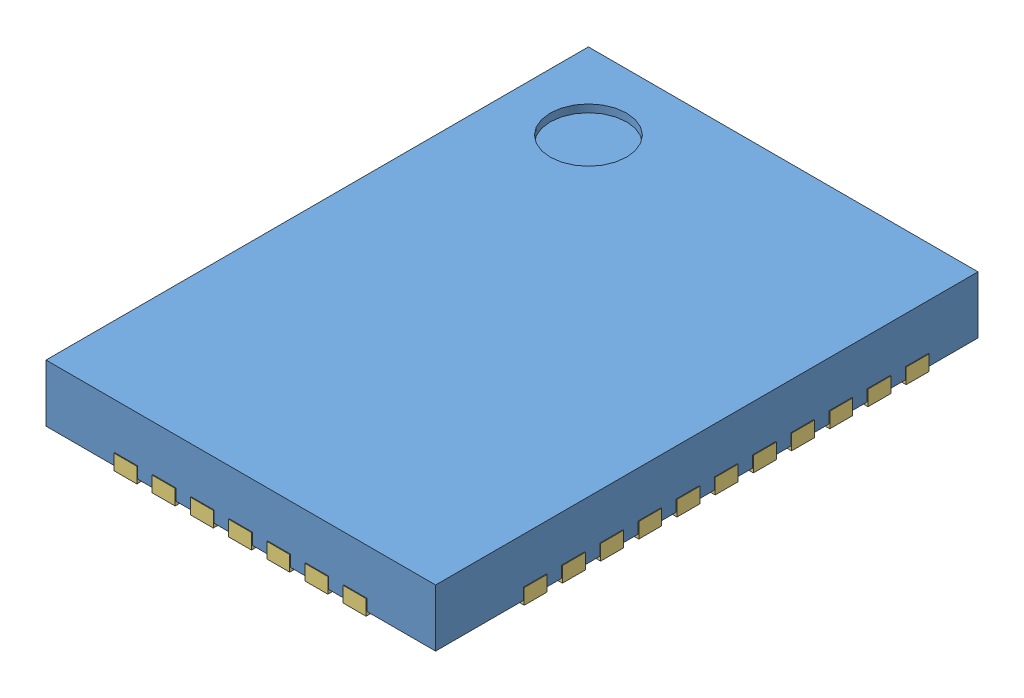
SolidWorks assembly LT-UHF38, configuration Default. Lengths in mm.
Overall size (5.12 0.8 7.12).
38 component instances, 3 part files, 12 mates.
Components (placement in the parent):
- Body-1: Body [Default] at (0 0.05 0) size (5.1 0.75 7.1)
- EP-1: EP [Default] at (0 0.2 0) x (-1 0 0) z (0 0 1) size (3.25 0.2 5.25)
- Pin-1: Pin [Default] at (-2.385 0 -2.75) size (0.5 0.2 0.3)
- Pin-2: Pin [Default] at (-2.385 0 -2.25) size (0.5 0.2 0.3)
- Pin-3: Pin [Default] at (-2.385 0 -1.75) size (0.5 0.2 0.3)
- Pin-4: Pin [Default] at (-2.385 0 -1.25) size (0.5 0.2 0.3)
- Pin-5: Pin [Default] at (-2.385 0 -0.75) size (0.5 0.2 0.3)
- Pin-6: Pin [Default] at (-2.385 0 -0.25) size (0.5 0.2 0.3)
- Pin-7: Pin [Default] at (-2.385 0 0.25) size (0.5 0.2 0.3)
- Pin-8: Pin [Default] at (-2.385 0 0.75) size (0.5 0.2 0.3)
- Pin-9: Pin [Default] at (-2.385 0 1.25) size (0.5 0.2 0.3)
- Pin-10: Pin [Default] at (-2.385 0 1.75) size (0.5 0.2 0.3)
- Pin-11: Pin [Default] at (-2.385 0 2.25) size (0.5 0.2 0.3)
- Pin-12: Pin [Default] at (2.385 0 -2.75) x (-1 0 0) z (0 0 -1) size (0.5 0.2 0.3)
- Pin-13: Pin [Default] at (2.385 0 -2.25) x (-1 0 0) z (0 0 -1) size (0.5 0.2 0.3)
- Pin-14: Pin [Default] at (2.385 0 -1.75) x (-1 0 0) z (0 0 -1) size (0.5 0.2 0.3)
- Pin-15: Pin [Default] at (2.385 0 -1.25) x (-1 0 0) z (0 0 -1) size (0.5 0.2 0.3)
- Pin-16: Pin [Default] at (2.385 0 -0.75) x (-1 0 0) z (0 0 -1) size (0.5 0.2 0.3)
- Pin-17: Pin [Default] at (2.385 0 -0.25) x (-1 0 0) z (0 0 -1) size (0.5 0.2 0.3)
- Pin-18: Pin [Default] at (2.385 0 0.25) x (-1 0 0) z (0 0 -1) size (0.5 0.2 0.3)
- Pin-19: Pin [Default] at (2.385 0 0.75) x (-1 0 0) z (0 0 -1) size (0.5 0.2 0.3)
- Pin-20: Pin [Default] at (2.385 0 1.25) x (-1 0 0) z (0 0 -1) size (0.5 0.2 0.3)
- Pin-21: Pin [Default] at (2.385 0 1.75) x (-1 0 0) z (0 0 -1) size (0.5 0.2 0.3)
- Pin-22: Pin [Default] at (2.385 0 2.25) x (-1 0 0) z (0 0 -1) size (0.5 0.2 0.3)
- Pin-23: Pin [Default] at (1.5 0 -3.385) x (0 0 1) z (-1 0 0) size (0.5 0.2 0.3)
- Pin-24: Pin [Default] at (1 0 -3.385) x (0 0 1) z (-1 0 0) size (0.5 0.2 0.3)
- Pin-25: Pin [Default] at (0.5 0 -3.385) x (0 0 1) z (-1 0 0) size (0.5 0.2 0.3)
- Pin-26: Pin [Default] at (0 0 -3.385) x (0 0 1) z (-1 0 0) size (0.5 0.2 0.3)
- Pin-27: Pin [Default] at (-0.5 0 -3.385) x (0 0 1) z (-1 0 0) size (0.5 0.2 0.3)
- Pin-28: Pin [Default] at (-1 0 -3.385) x (0 0 1) z (-1 0 0) size (0.5 0.2 0.3)
- Pin-29: Pin [Default] at (-1.5 0 -3.385) x (0 0 1) z (-1 0 0) size (0.5 0.2 0.3)
- Pin-30: Pin [Default] at (1.5 0 3.385) x (0 0 -1) z (1 0 0) size (0.5 0.2 0.3)
- Pin-31: Pin [Default] at (1 0 3.385) x (0 0 -1) z (1 0 0) size (0.5 0.2 0.3)
- Pin-32: Pin [Default] at (0.5 0 3.385) x (0 0 -1) z (1 0 0) size (0.5 0.2 0.3)
- Pin-33: Pin [Default] at (0 0 3.385) x (0 0 -1) z (1 0 0) size (0.5 0.2 0.3)
- Pin-34: Pin [Default] at (-0.5 0 3.385) x (0 0 -1) z (1 0 0) size (0.5 0.2 0.3)
- Pin-35: Pin [Default] at (-1 0 3.385) x (0 0 -1) z (1 0 0) size (0.5 0.2 0.3)
- Pin-36: Pin [Default] at (-1.5 0 3.385) x (0 0 -1) z (1 0 0) size (0.5 0.2 0.3)
Mates (geometry in assembly coordinates):
- Coincident1: coincident aligned: plane of Body-1 through (0 0.05 0) normal (1 0 0)
- Coincident2: coincident aligned: plane of Body-1 through (0 0.05 0) normal (0 0 1)
- Distance1: distance = 0.05 mm aligned: plane of Body-1 through (0 0.05 0) normal (0 1 0)
- Coincident4: coincident anti-aligned: plane of EP-1 through (0 0.2 0) normal (-1 0 0)
- Coincident5: coincident aligned: plane of EP-1 through (0 0.2 0) normal (0 0 1)
- Coincident6: coincident anti-aligned: plane of EP-1 through (0 0 0) normal (0 -1 0)
- Coincident7: coincident anti-aligned: plane of Pin-1 through (-2.21 0 -2.75) normal (0 -1 0)
- Distance2: distance = 2.75 mm: plane of assembly through (0 0 0) normal (0 0 1); plane of assembly; plane of Pin-1 through (-2.385 0 -2.75) normal (0 0 1)
- Distance3: distance = 0.01 mm aligned: plane of Pin-1 through (-2.56 0.2 -2.6) normal (-1 0 0); plane of Body-1 through (-2.55 0.8 3.55) normal (-1 0 0)
- Coincident10: coincident anti-aligned: plane of Pin-23 through (1.5 0 -3.21) normal (0 -1 0)
- Distance4: distance = 1.5 mm anti-aligned: plane of Pin-23 through (1.5 0 -3.385) normal (-1 0 0)
- Distance5: distance = 0.01 mm aligned: plane of Pin-23 through (1.35 0.2 -3.56) normal (0 0 -1); plane of Body-1 through (-2.55 0.8 -3.55) normal (0 0 -1)
